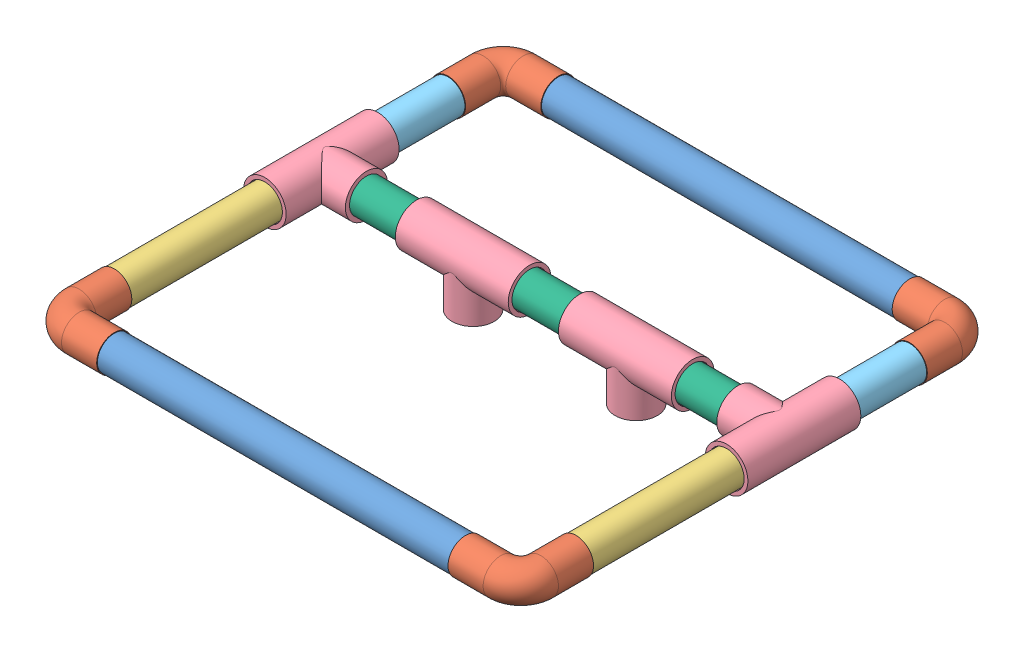
SolidWorks assembly basic_structure_right, configuration Default. Lengths in mm.
Overall size (320.45 108.06 303.21).
17 component instances, 6 part files, 40 mates.
Components (placement in the parent):
- PVC_tube_10-1: PVC_tube_10 [Default] at origin size (254 21.34 21.34)
- PVC_90-1: PVC_90 [Default] at (1.5875 0 -17.1322) x (-1 0 0) z (0 -1 0) size (46.04 46.04 22.23)
- PVC_90-2: PVC_90 [Default] at (-255.5875 0 -17.1322) x (1 0 0) z (0 1 0) size (46.04 46.04 22.23)
- PVC_tube_5-1: PVC_tube_5 [Default] at (19.05 0 -146.05) x (0 0 -1) z (-0.258772 -0.965938 0) size (127 21.34 21.34)
- PVC_tee-1: PVC_tee [Default] at (19.05 0 -165.8938) x (0 0 -1) z (0 1 0) size (71.44 48.76 26.99)
- PVC_tube_3-1: PVC_tube_3 [Default] at (19.05 0 -261.9375) x (0 0 -1) z (1 0 0) size (76.2 21.34 21.34)
- PVC_90-3: PVC_90 [Default] at (1.9178 0 -263.525) x (0 0 1) z (0 -1 0) size (46.04 46.04 22.23)
- PVC_tube_10-2: PVC_tube_10 [Default] at (0 0 -280.9875) size (254 21.34 21.34)
- PVC_90-4: PVC_90 [Default] at (-255.5875 0 -263.8553) x (1 0 0) z (0 -1 0) size (46.04 46.04 22.23)
- PVC_tee-2: PVC_tee [Default] at (-273.05 0 -165.8938) x (0 0 -1) z (0 -1 0) size (71.44 48.76 26.99)
- PVC_tube_3-2: PVC_tube_3 [Default] at (-273.05 0 -185.7375) x (0 0 1) z (0.996828 -0.079586 0) size (76.2 21.34 21.34)
- PVC_tube_5-2: PVC_tube_5 [Default] at (-273.05 0 -19.05) x (0 0 1) z (-0.574029 0.818835 0) size (127 21.34 21.34)
- PVC_tee-3: PVC_tee [Default] at (-177.0062 0 -165.8938) x (1 0 0) z (0 0 -1) size (71.44 48.76 26.99)
- PVC_tube_2.5-1: PVC_tube_2.5 [Default] at (-196.85 0 -165.8938) x (1 0 0) z (0 -0.97364 0.228092) size (63.5 21.34 21.34)
- PVC_tube_2.5-2: PVC_tube_2.5 [Default] at (-93.6625 0 -165.8938) x (1 0 0) z (0 -0.968379 0.249483) size (63.5 21.34 21.34)
- PVC_tee-5: PVC_tee [Default] at (-73.8188 0 -165.8938) x (1 0 0) z (0 0 -1) size (71.44 48.76 26.99)
- PVC_tube_2.5-3: PVC_tube_2.5 [Default] at (6.35 0 -165.8938) size (63.5 21.34 21.34)
Mates (geometry in assembly coordinates):
- Concentric1: concentric aligned: circle of PVC_tube_10-1; circle of PVC_90-1
- Distance1: distance = 15.875 mm anti-aligned: plane of PVC_tube_10-1 through (0 0 0) normal (1 0 0); plane of PVC_90-1 through (-15.875 0 0) normal (-1 0 0)
- Concentric2: concentric anti-aligned: circle of PVC_tube_10-1; circle of PVC_90-2
- Distance2: distance = 15.875 mm anti-aligned: plane of PVC_tube_10-1 through (-254 0 0) normal (-1 0 0); plane of PVC_90-2 through (-238.125 0 0) normal (1 0 0)
- Parallel1: parallel: plane of PVC_90-1 through (19.05 0 -34.925) normal (0 0 -1); line of assembly
- Parallel2: parallel: plane of PVC_90-2 through (-273.05 0 -34.925) normal (0 0 -1); line of assembly
- Concentric3: concentric anti-aligned: circle of PVC_90-1; circle of PVC_tube_5-1
- Distance3: distance = 15.875 mm anti-aligned: plane of PVC_tube_5-1 through (19.05 0 -19.05) normal (0 0 1); plane of PVC_90-1 through (19.05 0 -34.925) normal (0 0 -1)
- Concentric4: concentric aligned: circle of PVC_tube_5-1; circle of PVC_tee-1
- Distance4: distance = 15.875 mm anti-aligned: plane of PVC_tee-1 through (19.05 0 -130.175) normal (0 0 1); plane of PVC_tube_5-1 through (19.05 0 -146.05) normal (0 0 -1)
- Parallel3: parallel aligned: line of ? through (19.05 0 -165.8938) axis (-1 0 0)
- Concentric5: concentric aligned: circle of PVC_tee-1; circle of PVC_tube_3-1
- Distance5: distance = 15.875 mm anti-aligned: plane of PVC_tube_3-1 through (19.05 0 -185.7375) normal (0 0 1); plane of PVC_tee-1 through (19.05 0 -201.6125) normal (0 0 -1)
- Concentric7: concentric anti-aligned: circle of PVC_tube_3-1; circle of PVC_90-3
- Distance6: distance = 15.875 mm anti-aligned: plane of PVC_90-3 through (19.05 0 -246.0625) normal (0 0 1); plane of PVC_tube_3-1 through (19.05 0 -261.9375) normal (0 0 -1)
- Perpendicular2: perpendicular: plane of PVC_90-3 through (-15.875 0 -280.9875) normal (-1 0 0); line of assembly
- Concentric8: concentric anti-aligned: circle of PVC_90-3; circle of PVC_tube_10-2
- Distance7: distance = 15.875 mm anti-aligned: plane of PVC_tube_10-2 through (0 0 -280.9875) normal (1 0 0); plane of PVC_90-3 through (-15.875 0 -280.9875) normal (-1 0 0)
- Distance8: distance = 15.875 mm anti-aligned: plane of PVC_90-4 through (-238.125 0 -280.9875) normal (1 0 0); plane of PVC_tube_10-2 through (-254 0 -280.9875) normal (-1 0 0)
- Concentric9: concentric aligned: circle of PVC_tube_10-2; circle of PVC_90-4
- Parallel8: parallel: plane of PVC_90-4 through (-273.05 0 -246.0625) normal (0 0 1); line of assembly
- Concentric10: concentric aligned: cylinder of PVC_90-4 through (-273.05 0 -246.0625) axis (0 0 -1) radius 11.1125; circle of PVC_tee-2
- Concentric11: concentric anti-aligned: circle of PVC_90-4; circle of PVC_tube_3-2
- Distance10: distance = 15.875 mm anti-aligned: plane of PVC_tube_3-2 through (-273.05 0 -261.9375) normal (0 0 -1); plane of PVC_90-4 through (-273.05 0 -246.0625) normal (0 0 1)
- Distance11: distance = 15.875 mm anti-aligned: plane of PVC_tee-2 through (-273.05 0 -201.6125) normal (0 0 -1); plane of PVC_tube_3-2 through (-273.05 0 -185.7375) normal (0 0 1)
- Concentric12: concentric anti-aligned: circle of PVC_tee-2; circle of PVC_tube_5-2
- Parallel9: parallel anti-aligned: line of ? through (-273.05 0 -165.8938) axis (1 0 0)
- Distance13: distance = 15.875 mm anti-aligned: plane of PVC_tube_5-2 through (-273.05 0 -19.05) normal (0 0 1); plane of PVC_90-2 through (-273.05 0 -34.925) normal (0 0 -1)
- Concentric13: concentric aligned: circle of PVC_tee-2; cylinder of PVC_tube_2.5-1 through (-260.35 0 -165.8938) axis (1 0 0) radius 10.668
- Distance14: distance = 15.875 mm anti-aligned: plane of PVC_tube_2.5-1 through (-260.35 0 -165.8938) normal (-1 0 0); plane of PVC_tee-2 through (-244.475 0 -165.8938) normal (1 0 0)
- Concentric14: concentric aligned: circle of PVC_tee-3; circle of PVC_tube_2.5-1
- Distance15: distance = 15.875 mm anti-aligned: plane of PVC_tee-3 through (-212.725 0 -165.8938) normal (-1 0 0); plane of PVC_tube_2.5-1 through (-196.85 0 -165.8938) normal (1 0 0)
- Concentric15: concentric aligned: circle of PVC_tee-3; circle of PVC_tube_2.5-2
- Distance16: distance = 15.875 mm anti-aligned: plane of PVC_tube_2.5-2 through (-157.1625 0 -165.8938) normal (-1 0 0); plane of PVC_tee-3 through (-141.2875 0 -165.8938) normal (1 0 0)
- Concentric16: concentric aligned: circle of PVC_tube_2.5-2; circle of PVC_tee-5
- Distance17: distance = 15.875 mm anti-aligned: plane of PVC_tee-5 through (-109.5375 0 -165.8938) normal (-1 0 0); plane of PVC_tube_2.5-2 through (-93.6625 0 -165.8938) normal (1 0 0)
- Concentric17: concentric anti-aligned: circle of PVC_tee-1; circle of PVC_tube_2.5-3
- Distance18: distance = 15.875 mm anti-aligned: plane of PVC_tube_2.5-3 through (6.35 0 -165.8938) normal (1 0 0); plane of PVC_tee-1 through (-9.525 0 -165.8938) normal (-1 0 0)
- Parallel10: parallel anti-aligned: line of ? through (-73.8188 0 -165.8938) axis (0 -1 0)
- Parallel11: parallel anti-aligned: line of PVC_tee-3 through (-177.0062 0 -165.8938) axis (0 -1 0); line of assembly
